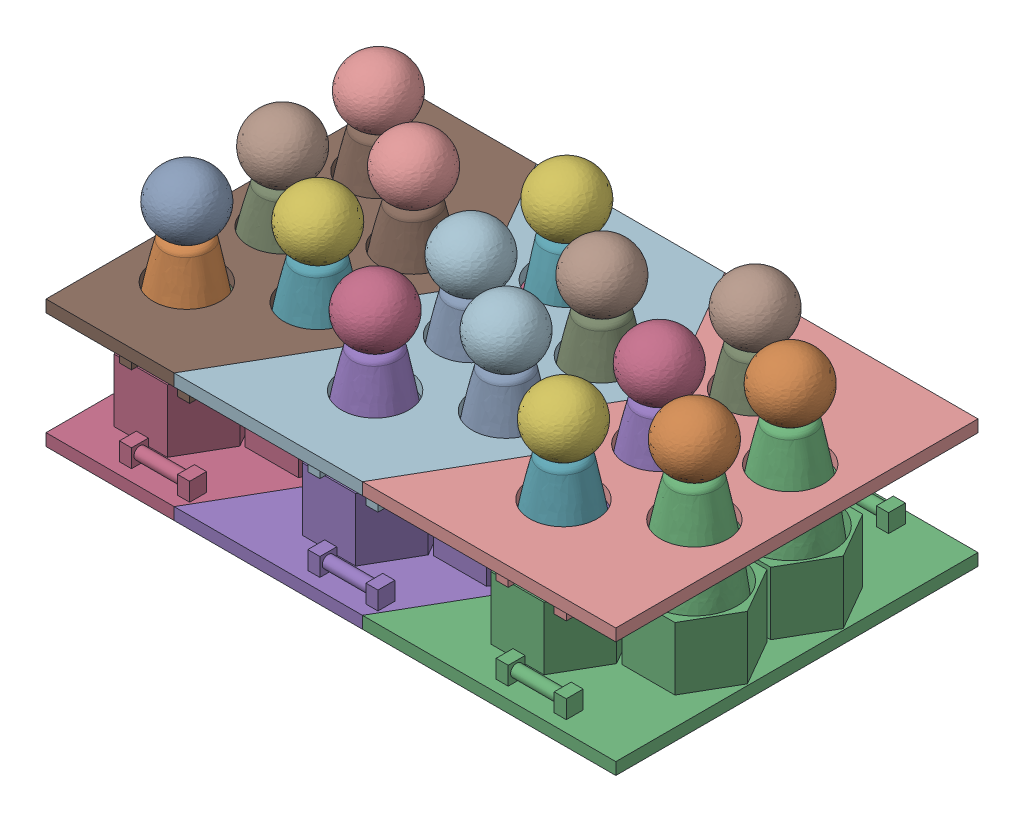
SolidWorks assembly Passenger tray, configuration Default. Lengths in mm.
Overall size (236.97 94.5 150).
17 component instances, 3 part files, 34 mates.
Components (placement in the parent):
- crew-passenger-1: crew-passenger [Default] at (-49.5312 15.4653 -45.3397) size (36.14 88.9 36.75)
- hex_passenger_flooring final plate-1: hex_passenger_flooring final plate [Default] at (45.4688 12.3653 -85.0272) size (236 31 150)
- crew-passenger-2: crew-passenger [Default] at (-15.1609 15.4653 -65.1835) size (36.14 88.9 36.75)
- crew-passenger-3: crew-passenger [Default] at (62.8391 15.4653 -104.871) size (36.14 88.9 36.75)
- crew-passenger-4: crew-passenger [Default] at (-49.5312 15.4653 -124.7147) size (36.14 88.9 36.75)
- crew-passenger-5: crew-passenger [Default] at (62.8391 15.4653 -65.1835) size (36.14 88.9 36.75)
- crew-passenger-6: crew-passenger [Default] at (140.8391 15.4653 -104.871) size (36.14 88.9 36.75)
- crew-passenger-7: crew-passenger [Default] at (106.4688 15.4653 -85.0272) size (36.14 88.9 36.75)
- crew-passenger-8: crew-passenger [Default] at (106.4688 15.4653 -45.3397) size (36.14 88.9 36.75)
- crew-passenger-9: crew-passenger [Default] at (106.4688 15.4653 -124.7147) size (36.14 88.9 36.75)
- crew-passenger-10: crew-passenger [Default] at (-15.1609 15.4653 -104.871) x (0.986442 0 -0.164112) z (0.164112 0 0.986442) size (36.14 88.9 36.75)
- crew-passenger-11: crew-passenger [Default] at (28.4688 15.4653 -85.0272) size (36.14 88.9 36.75)
- crew-passenger-12: crew-passenger [Default] at (140.8391 15.4653 -65.1835) size (36.14 88.9 36.75)
- crew-passenger-13: crew-passenger [Default] at (28.4688 15.4653 -45.3397) size (36.14 88.9 36.75)
- crew-passenger-14: crew-passenger [Default] at (28.4688 15.4653 -124.7147) x (-0.140851 0 -0.990031) z (0.990031 0 -0.140851) size (36.14 88.9 36.75)
- crew-passenger-15: crew-passenger [Default] at (-49.5312 15.4653 -85.0272) x (0.914163 0 -0.405346) z (0.405346 0 0.914163) size (36.14 88.9 36.75)
- Passenger tray seatbelt-1: Passenger tray seatbelt [Default] at (45.4688 60.2976 -85.0272) x (1 0 0) z (0 0 -1) size (236 12.5 150)
Mates (geometry in assembly coordinates):
- Coincident1: coincident aligned: plane of crew-passenger-1 through (-49.5312 15.4653 -45.3397) normal (0 -1 0); plane of crew-passenger-2 through (-15.1609 15.4653 -65.1835) normal (0 -1 0)
- Coincident2: coincident aligned: plane of crew-passenger-2 through (-15.1609 15.4653 -65.1835) normal (0 -1 0); plane of crew-passenger-5 through (62.8391 15.4653 -65.1835) normal (0 -1 0)
- Coincident3: coincident aligned: plane of crew-passenger-3 through (62.8391 15.4653 -104.871) normal (0 -1 0); plane of crew-passenger-5 through (62.8391 15.4653 -65.1835) normal (0 -1 0)
- Coincident4: coincident aligned: plane of crew-passenger-3 through (62.8391 15.4653 -104.871) normal (0 -1 0); plane of crew-passenger-8 through (106.4688 15.4653 -45.3397) normal (0 -1 0)
- Coincident5: coincident aligned: plane of crew-passenger-7 through (106.4688 15.4653 -85.0272) normal (0 -1 0); plane of crew-passenger-8 through (106.4688 15.4653 -45.3397) normal (0 -1 0)
- Coincident6: coincident aligned: plane of crew-passenger-7 through (106.4688 15.4653 -85.0272) normal (0 -1 0); plane of crew-passenger-10 through (-15.1609 15.4653 -104.871) normal (0 -1 0)
- Coincident7: coincident aligned: plane of crew-passenger-10 through (-15.1609 15.4653 -104.871) normal (0 -1 0); plane of crew-passenger-13 through (28.4688 15.4653 -45.3397) normal (0 -1 0)
- Coincident8: coincident aligned: plane of crew-passenger-12 through (140.8391 15.4653 -65.1835) normal (0 -1 0); plane of crew-passenger-13 through (28.4688 15.4653 -45.3397) normal (0 -1 0)
- Coincident9: coincident aligned: plane of crew-passenger-14 through (28.4688 15.4653 -124.7147) normal (0 -1 0); plane of crew-passenger-15 through (-49.5312 15.4653 -85.0272) normal (0 -1 0)
- Coincident10: coincident aligned: plane of crew-passenger-11 through (28.4688 15.4653 -85.0272) normal (0 -1 0); plane of crew-passenger-14 through (28.4688 15.4653 -124.7147) normal (0 -1 0)
- Coincident11: coincident aligned: plane of crew-passenger-9 through (106.4688 15.4653 -124.7147) normal (0 -1 0); plane of crew-passenger-14 through (28.4688 15.4653 -124.7147) normal (0 -1 0)
- Coincident12: coincident aligned: plane of crew-passenger-6 through (140.8391 15.4653 -104.871) normal (0 -1 0); plane of crew-passenger-4 through (-49.5312 15.4653 -124.7147) normal (0 -1 0)
- Coincident13: coincident aligned: plane of crew-passenger-4 through (-49.5312 15.4653 -124.7147) normal (0 -1 0); plane of crew-passenger-15 through (-49.5312 15.4653 -85.0272) normal (0 -1 0)
- Coincident14: coincident aligned: plane of crew-passenger-12 through (140.8391 15.4653 -65.1835) normal (0 -1 0); plane of crew-passenger-14 through (28.4688 15.4653 -124.7147) normal (0 -1 0)
- Concentric1: concentric anti-aligned: cylinder of hex_passenger_flooring final plate-1 through (-49.5312 15.4653 -124.7147) axis (0 1 0) radius 13.97; cylinder of crew-passenger-4 through (-49.5312 19.9103 -124.7147) axis (0 -1 0) radius 13.97
- Concentric2: concentric anti-aligned: cylinder of hex_passenger_flooring final plate-1 through (-49.5312 15.4653 -85.0272) axis (0 1 0) radius 13.97; cylinder of crew-passenger-15 through (-49.5312 19.9103 -85.0272) axis (0 -1 0) radius 13.97
- Concentric3: concentric anti-aligned: cylinder of crew-passenger-1 through (-49.5312 19.9103 -45.3397) axis (0 -1 0) radius 13.97; cylinder of hex_passenger_flooring final plate-1 through (-49.5312 15.4653 -45.3397) axis (0 1 0) radius 13.97
- Concentric4: concentric aligned: circle of hex_passenger_flooring final plate-1; cylinder of crew-passenger-2 through (-15.1609 19.9103 -65.1835) axis (0 -1 0) radius 13.97
- Concentric5: concentric aligned: circle of hex_passenger_flooring final plate-1; cylinder of crew-passenger-10 through (-15.1609 19.9103 -104.871) axis (0 -1 0) radius 13.97
- Concentric6: concentric anti-aligned: cylinder of hex_passenger_flooring final plate-1 through (28.4688 15.4653 -45.3397) axis (0 1 0) radius 13.97; cylinder of crew-passenger-13 through (28.4688 19.9103 -45.3397) axis (0 -1 0) radius 13.97
- Concentric7: concentric anti-aligned: cylinder of hex_passenger_flooring final plate-1 through (62.8391 15.4653 -104.871) axis (0 1 0) radius 13.97; cylinder of crew-passenger-3 through (62.8391 19.9103 -104.871) axis (0 -1 0) radius 13.97
- Concentric8: concentric anti-aligned: cylinder of hex_passenger_flooring final plate-1 through (28.4688 15.4653 -85.0272) axis (0 1 0) radius 13.97; cylinder of crew-passenger-11 through (28.4688 19.9103 -85.0272) axis (0 -1 0) radius 13.97
- Concentric9: concentric anti-aligned: cylinder of hex_passenger_flooring final plate-1 through (28.4688 15.4653 -124.7147) axis (0 1 0) radius 13.97; cylinder of crew-passenger-14 through (28.4688 19.9103 -124.7147) axis (0 -1 0) radius 13.97
- Concentric10: concentric anti-aligned: cylinder of hex_passenger_flooring final plate-1 through (106.4688 15.4653 -124.7147) axis (0 1 0) radius 13.97; cylinder of crew-passenger-9 through (106.4688 19.9103 -124.7147) axis (0 -1 0) radius 13.97
- Concentric11: concentric anti-aligned: cylinder of hex_passenger_flooring final plate-1 through (62.8391 15.4653 -65.1835) axis (0 1 0) radius 13.97; cylinder of crew-passenger-5 through (62.8391 19.9103 -65.1835) axis (0 -1 0) radius 13.97
- Concentric12: concentric anti-aligned: cylinder of hex_passenger_flooring final plate-1 through (140.8391 15.4653 -104.871) axis (0 1 0) radius 13.97; cylinder of crew-passenger-6 through (140.8391 19.9103 -104.871) axis (0 -1 0) radius 13.97
- Concentric13: concentric anti-aligned: cylinder of hex_passenger_flooring final plate-1 through (140.8391 15.4653 -65.1835) axis (0 1 0) radius 13.97; cylinder of crew-passenger-12 through (140.8391 19.9103 -65.1835) axis (0 -1 0) radius 13.97
- Concentric14: concentric anti-aligned: cylinder of crew-passenger-8 through (106.4688 19.9103 -45.3397) axis (0 -1 0) radius 13.97; cylinder of hex_passenger_flooring final plate-1 through (106.4688 15.4653 -45.3397) axis (0 1 0) radius 13.97
- Concentric15: concentric anti-aligned: cylinder of hex_passenger_flooring final plate-1 through (106.4688 15.4653 -85.0272) axis (0 1 0) radius 13.97; cylinder of crew-passenger-7 through (106.4688 19.9103 -85.0272) axis (0 -1 0) radius 13.97
- Coincident15: coincident anti-aligned: plane of hex_passenger_flooring final plate-1 through (28.4688 15.4653 -85.0272) normal (0 1 0); plane of crew-passenger-11 through (28.4688 15.4653 -85.0272) normal (0 -1 0)
- Concentric16: concentric aligned: cylinder of hex_passenger_flooring final plate-1 through (-49.5312 19.3108 -124.7147) axis (0 1 0) radius 17.907; cylinder of Passenger_seatbelt_block-1 through (-49.5312 103.0817 -124.7147) axis (0 1 0) radius 15.875
- Concentric17: concentric anti-aligned: cylinder of hex_passenger_flooring final plate-1 through (-49.5312 19.3108 -45.3397) axis (0 1 0) radius 17.907; cylinder of Passenger tray seatbelt-1 through (-49.5312 68.1976 -45.3397) axis (0 -1 0) radius 13.97
- Concentric18: concentric anti-aligned: cylinder of hex_passenger_flooring final plate-1 through (140.8391 19.3108 -104.871) axis (0 1 0) radius 17.907; cylinder of Passenger tray seatbelt-1 through (140.8391 68.1976 -104.871) axis (0 -1 0) radius 13.97
- Coincident16: coincident aligned: plane of hex_passenger_flooring final plate-1 through (138.179 22.3653 -148.2647) normal (1 0 0); plane of Passenger tray seatbelt-1 through (138.179 50.2976 -85.0272) normal (1 0 0)
